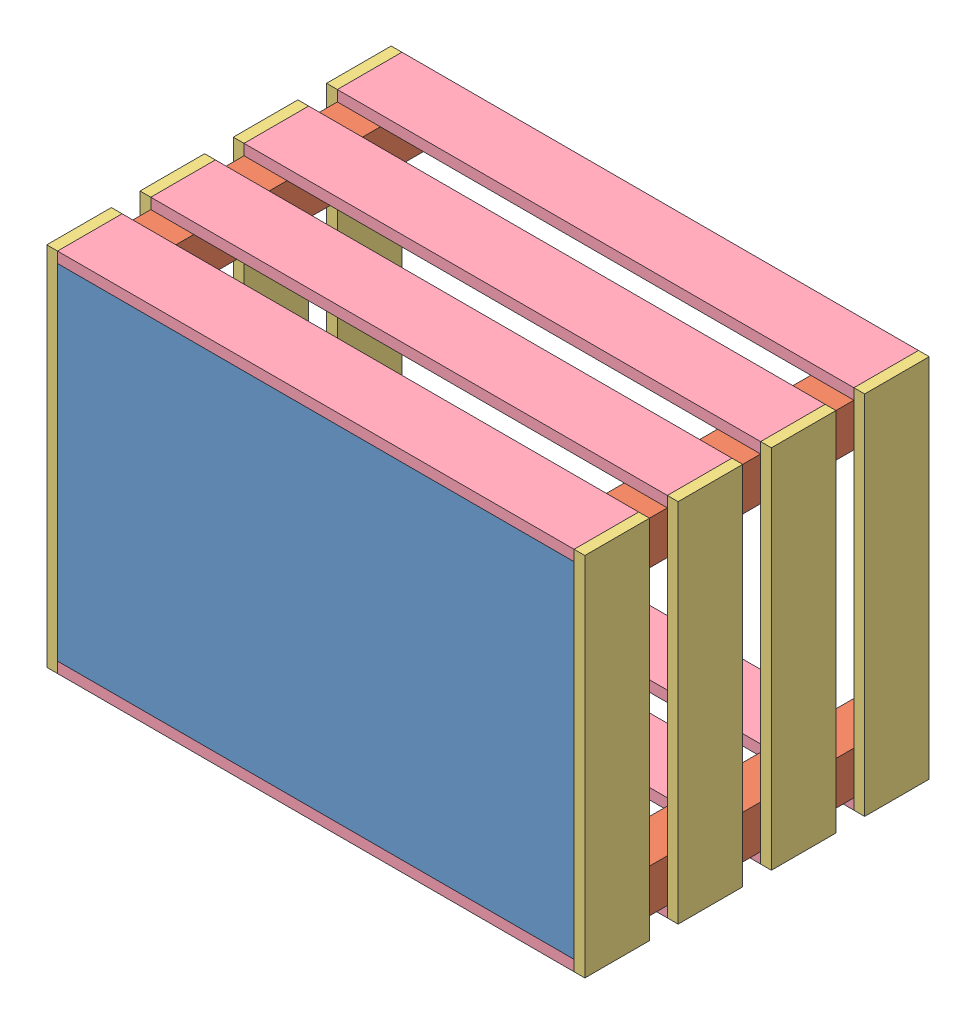
SolidWorks assembly crate, configuration Default. Lengths in mm.
Overall size (317.5 215.9 203.2).
21 component instances, 4 part files, 60 mates.
Components (placement in the parent):
- bottom-1: bottom [Default] at (-1.7472 114.5452 325.1624) size (304.8 203.2 6.35)
- post-1: post [Default] at (-1.7472 114.5452 128.3124) size (25.4 25.4 196.85)
- post-2: post [Default] at (-1.7472 292.3452 128.3124) size (25.4 25.4 196.85)
- post-5: post [Default] at (277.6528 114.5452 128.3124) size (25.4 25.4 196.85)
- post-7: post [Default] at (277.6528 292.3452 128.3124) size (25.4 25.4 196.85)
- side width-1: side width [Default] at (-1.7472 324.0952 293.4124) x (0 -1 0) z (-1 0 0) size (215.9 38.1 6.35)
- side width-2: side width [Default] at (-1.7472 108.1952 166.4124) x (0 1 0) z (-1 0 0) size (215.9 38.1 6.35)
- side width-3: side width [Default] at (-1.7472 324.0952 183.3458) x (0 -1 0) z (-1 0 0) size (215.9 38.1 6.35)
- side width-4: side width [Default] at (-1.7472 324.0952 238.3791) x (0 -1 0) z (-1 0 0) size (215.9 38.1 6.35)
- side width-5: side width [Default] at (309.4028 324.0952 293.4124) x (0 -1 0) z (-1 0 0) size (215.9 38.1 6.35)
- side width-6: side width [Default] at (309.4028 324.0952 238.3791) x (0 -1 0) z (-1 0 0) size (215.9 38.1 6.35)
- side width-7: side width [Default] at (309.4028 324.0952 183.3458) x (0 -1 0) z (-1 0 0) size (215.9 38.1 6.35)
- side width-8: side width [Default] at (309.4028 324.0952 128.3124) x (0 -1 0) z (-1 0 0) size (215.9 38.1 6.35)
- side length-1: side length [Default] at (-1.7472 114.5452 293.4124) x (1 0 0) z (0 -1 0) size (304.8 38.1 6.35)
- side length-2: side length [Default] at (-1.7472 114.5452 183.3458) x (1 0 0) z (0 -1 0) size (304.8 38.1 6.35)
- side length-3: side length [Default] at (-1.7472 114.5452 238.3791) x (1 0 0) z (0 -1 0) size (304.8 38.1 6.35)
- side length-4: side length [Default] at (-1.7472 114.5452 128.3124) x (1 0 0) z (0 -1 0) size (304.8 38.1 6.35)
- side length-5: side length [Default] at (-1.7472 324.0952 293.4124) x (1 0 0) z (0 -1 0) size (304.8 38.1 6.35)
- side length-6: side length [Default] at (-1.7472 324.0952 128.3124) x (1 0 0) z (0 -1 0) size (304.8 38.1 6.35)
- side length-7: side length [Default] at (-1.7472 324.0952 183.3458) x (1 0 0) z (0 -1 0) size (304.8 38.1 6.35)
- side length-8: side length [Default] at (-1.7472 324.0952 238.3791) x (1 0 0) z (0 -1 0) size (304.8 38.1 6.35)
Mates (geometry in assembly coordinates):
- Coincident6: coincident anti-aligned: plane of bottom-1 through (-1.7472 114.5452 325.1624) normal (0 0 -1); plane of post-1 through (-1.7472 114.5452 325.1624) normal (0 0 1)
- Coincident7: coincident anti-aligned: plane of bottom-1 through (-1.7472 114.5452 325.1624) normal (0 0 -1); plane of post-2 through (-1.7472 292.3452 325.1624) normal (0 0 1)
- Coincident8: coincident aligned: plane of bottom-1 through (-1.7472 114.5452 331.5124) normal (-1 0 0); plane of post-2 through (-1.7472 292.3452 325.1624) normal (-1 0 0)
- Coincident9: coincident aligned: plane of bottom-1 through (-1.7472 317.7452 331.5124) normal (0 1 0); plane of post-2 through (-1.7472 317.7452 325.1624) normal (0 1 0)
- Coincident10: coincident anti-aligned: plane of bottom-1 through (-1.7472 114.5452 325.1624) normal (0 0 -1); plane of post-5 through (277.6528 114.5452 325.1624) normal (0 0 1)
- Coincident11: coincident aligned: plane of bottom-1 through (303.0528 114.5452 331.5124) normal (1 0 0); plane of post-5 through (303.0528 114.5452 325.1624) normal (1 0 0)
- Coincident12: coincident aligned: plane of bottom-1 through (-1.7472 114.5452 331.5124) normal (0 -1 0); plane of post-5 through (277.6528 114.5452 325.1624) normal (0 -1 0)
- Coincident13: coincident anti-aligned: plane of bottom-1 through (-1.7472 114.5452 325.1624) normal (0 0 -1); plane of post-7 through (277.6528 292.3452 325.1624) normal (0 0 1)
- Coincident14: coincident aligned: plane of bottom-1 through (303.0528 114.5452 331.5124) normal (1 0 0); plane of post-7 through (303.0528 292.3452 325.1624) normal (1 0 0)
- Coincident15: coincident aligned: plane of bottom-1 through (-1.7472 317.7452 331.5124) normal (0 1 0); plane of post-7 through (277.6528 317.7452 325.1624) normal (0 1 0)
- Coincident16: coincident anti-aligned: plane of bottom-1 through (-1.7472 114.5452 331.5124) normal (-1 0 0); plane of side width-1 through (-1.7472 324.0952 293.4124) normal (1 0 0)
- Coincident17: coincident aligned: plane of bottom-1 through (-1.7472 114.5452 331.5124) normal (0 0 1); plane of side width-1 through (-8.0972 324.0952 331.5124) normal (0 0 1)
- Distance1: distance = 6.35 mm aligned: plane of bottom-1 through (-1.7472 317.7452 331.5124) normal (0 1 0); plane of side width-1 through (-8.0972 324.0952 293.4124) normal (0 1 0)
- Coincident21: coincident aligned: plane of side width-1 through (-1.7472 324.0952 293.4124) normal (1 0 0); plane of side width-2 through (-1.7472 108.1952 166.4124) normal (1 0 0)
- Coincident22: coincident aligned: plane of post-2 through (-1.7472 292.3452 128.3124) normal (0 0 -1); plane of side width-2 through (-8.0972 108.1952 128.3124) normal (0 0 -1)
- Coincident23: coincident aligned: plane of side width-1 through (-8.0972 324.0952 293.4124) normal (0 1 0); plane of side width-2 through (-8.0972 324.0952 166.4124) normal (0 1 0)
- Coincident30: coincident aligned: plane of side width-1 through (-1.7472 324.0952 293.4124) normal (1 0 0); plane of side width-4 through (-1.7472 324.0952 238.3791) normal (1 0 0)
- Coincident31: coincident aligned: plane of side width-1 through (-1.7472 324.0952 293.4124) normal (1 0 0); plane of side width-3 through (-1.7472 324.0952 183.3458) normal (1 0 0)
- Coincident32: coincident aligned: plane of side width-1 through (-8.0972 324.0952 293.4124) normal (0 1 0); plane of side width-4 through (-8.0972 324.0952 238.3791) normal (0 1 0)
- Coincident33: coincident aligned: plane of side width-1 through (-8.0972 324.0952 293.4124) normal (0 1 0); plane of side width-3 through (-8.0972 324.0952 183.3458) normal (0 1 0)
- Distance4: distance = 16.9333 mm anti-aligned: plane of side width-4 through (-8.0972 324.0952 276.4791) normal (0 0 1); plane of side width-1 through (-8.0972 324.0952 293.4124) normal (0 0 -1)
- Distance5: distance = 16.9333 mm anti-aligned: plane of side width-4 through (-8.0972 324.0952 238.3791) normal (0 0 -1); plane of side width-3 through (-8.0972 324.0952 221.4458) normal (0 0 1)
- Coincident37: coincident anti-aligned: plane of bottom-1 through (303.0528 114.5452 331.5124) normal (1 0 0); plane of side width-5 through (303.0528 324.0952 293.4124) normal (-1 0 0)
- Coincident38: coincident aligned: plane of bottom-1 through (-1.7472 114.5452 331.5124) normal (0 0 1); plane of side width-5 through (303.0528 324.0952 331.5124) normal (0 0 1)
- Distance7: distance = 6.35 mm aligned: plane of post-7 through (277.6528 317.7452 325.1624) normal (0 1 0); plane of side width-5 through (303.0528 324.0952 293.4124) normal (0 1 0)
- Coincident41: coincident aligned: plane of side width-5 through (303.0528 324.0952 293.4124) normal (-1 0 0); plane of side width-6 through (303.0528 324.0952 238.3791) normal (-1 0 0)
- Coincident42: coincident aligned: plane of side width-5 through (303.0528 324.0952 293.4124) normal (-1 0 0); plane of side width-7 through (303.0528 324.0952 183.3458) normal (-1 0 0)
- Coincident43: coincident aligned: plane of side width-5 through (303.0528 324.0952 293.4124) normal (-1 0 0); plane of side width-8 through (303.0528 324.0952 128.3124) normal (-1 0 0)
- Coincident44: coincident aligned: plane of side width-5 through (303.0528 324.0952 293.4124) normal (0 1 0); plane of side width-6 through (303.0528 324.0952 238.3791) normal (0 1 0)
- Coincident45: coincident aligned: plane of side width-5 through (303.0528 324.0952 293.4124) normal (0 1 0); plane of side width-7 through (303.0528 324.0952 183.3458) normal (0 1 0)
- Coincident46: coincident aligned: plane of side width-5 through (303.0528 324.0952 293.4124) normal (0 1 0); plane of side width-8 through (303.0528 324.0952 128.3124) normal (0 1 0)
- Coincident47: coincident aligned: plane of post-7 through (277.6528 292.3452 128.3124) normal (0 0 -1); plane of side width-8 through (303.0528 324.0952 128.3124) normal (0 0 -1)
- Distance8: distance = 16.9333 mm anti-aligned: plane of side width-5 through (303.0528 324.0952 293.4124) normal (0 0 -1); plane of side width-6 through (303.0528 324.0952 276.4791) normal (0 0 1)
- Distance9: distance = 16.9333 mm anti-aligned: plane of side width-7 through (303.0528 324.0952 221.4458) normal (0 0 1); plane of side width-6 through (303.0528 324.0952 238.3791) normal (0 0 -1)
- Coincident51: coincident anti-aligned: plane of post-5 through (277.6528 114.5452 325.1624) normal (0 -1 0); plane of side length-1 through (-1.7472 114.5452 293.4124) normal (0 1 0)
- Coincident52: coincident aligned: plane of bottom-1 through (-1.7472 114.5452 331.5124) normal (0 0 1); plane of side length-1 through (-1.7472 108.1952 331.5124) normal (0 0 1)
- Coincident55: coincident aligned: plane of bottom-1 through (-1.7472 114.5452 331.5124) normal (0 -1 0); plane of post-1 through (-1.7472 114.5452 325.1624) normal (0 -1 0)
- Coincident56: coincident anti-aligned: plane of post-1 through (-1.7472 114.5452 325.1624) normal (-1 0 0); plane of side width-1 through (-1.7472 324.0952 293.4124) normal (1 0 0)
- Coincident57: coincident aligned: plane of post-1 through (-1.7472 114.5452 325.1624) normal (-1 0 0); plane of side length-1 through (-1.7472 108.1952 293.4124) normal (-1 0 0)
- Coincident58: coincident aligned: plane of side length-1 through (-1.7472 114.5452 293.4124) normal (0 1 0); plane of side length-4 through (-1.7472 114.5452 128.3124) normal (0 1 0)
- Coincident59: coincident aligned: plane of side length-1 through (-1.7472 114.5452 293.4124) normal (0 1 0); plane of side length-2 through (-1.7472 114.5452 183.3458) normal (0 1 0)
- Coincident60: coincident aligned: plane of side length-1 through (-1.7472 114.5452 293.4124) normal (0 1 0); plane of side length-3 through (-1.7472 114.5452 238.3791) normal (0 1 0)
- Coincident61: coincident aligned: plane of post-1 through (-1.7472 114.5452 325.1624) normal (-1 0 0); plane of side length-4 through (-1.7472 108.1952 128.3124) normal (-1 0 0)
- Coincident62: coincident aligned: plane of post-1 through (-1.7472 114.5452 325.1624) normal (-1 0 0); plane of side length-2 through (-1.7472 108.1952 183.3458) normal (-1 0 0)
- Coincident63: coincident aligned: plane of post-1 through (-1.7472 114.5452 325.1624) normal (-1 0 0); plane of side length-3 through (-1.7472 108.1952 238.3791) normal (-1 0 0)
- Coincident64: coincident aligned: plane of post-1 through (-1.7472 114.5452 128.3124) normal (0 0 -1); plane of side length-4 through (-1.7472 108.1952 128.3124) normal (0 0 -1)
- Distance12: distance = 16.9333 mm anti-aligned: plane of side length-1 through (-1.7472 108.1952 293.4124) normal (0 0 -1); plane of side length-3 through (-1.7472 108.1952 276.4791) normal (0 0 1)
- Distance13: distance = 16.9333 mm anti-aligned: plane of side length-3 through (-1.7472 108.1952 238.3791) normal (0 0 -1); plane of side length-2 through (-1.7472 108.1952 221.4458) normal (0 0 1)
- Coincident71: coincident anti-aligned: plane of bottom-1 through (-1.7472 317.7452 331.5124) normal (0 1 0); plane of side length-5 through (-1.7472 317.7452 293.4124) normal (0 -1 0)
- Coincident72: coincident aligned: plane of bottom-1 through (-1.7472 114.5452 331.5124) normal (0 0 1); plane of side length-5 through (-1.7472 317.7452 331.5124) normal (0 0 1)
- Coincident73: coincident aligned: plane of post-7 through (303.0528 292.3452 325.1624) normal (1 0 0); plane of side length-5 through (303.0528 317.7452 293.4124) normal (1 0 0)
- Coincident74: coincident aligned: plane of side length-5 through (-1.7472 317.7452 293.4124) normal (0 -1 0); plane of side length-7 through (-1.7472 317.7452 399.3489) normal (0 -1 0)
- Coincident75: coincident aligned: plane of side length-5 through (-1.7472 317.7452 293.4124) normal (0 -1 0); plane of side length-6 through (-1.7472 317.7452 128.3124) normal (0 -1 0)
- Coincident76: coincident aligned: plane of side length-5 through (-1.7472 317.7452 293.4124) normal (0 -1 0); plane of side length-8 through (-1.7472 317.7452 238.3791) normal (0 -1 0)
- Coincident77: coincident aligned: plane of post-7 through (303.0528 292.3452 325.1624) normal (1 0 0); plane of side length-7 through (303.0528 317.7452 399.3489) normal (1 0 0)
- Coincident79: coincident aligned: plane of post-7 through (303.0528 292.3452 325.1624) normal (1 0 0); plane of side length-6 through (303.0528 317.7452 128.3124) normal (1 0 0)
- Coincident80: coincident aligned: plane of post-7 through (303.0528 292.3452 325.1624) normal (1 0 0); plane of side length-8 through (303.0528 317.7452 238.3791) normal (1 0 0)
- Coincident82: coincident aligned: plane of post-7 through (277.6528 292.3452 128.3124) normal (0 0 -1); plane of side length-6 through (-1.7472 317.7452 128.3124) normal (0 0 -1)
- Distance14: distance = 16.9333 mm anti-aligned: plane of side length-5 through (-1.7472 317.7452 293.4124) normal (0 0 -1); plane of side length-8 through (-1.7472 317.7452 276.4791) normal (0 0 1)
- Distance15: distance = 16.9333 mm anti-aligned: plane of side length-8 through (-1.7472 317.7452 238.3791) normal (0 0 -1); plane of side length-7 through (-1.7472 317.7452 221.4458) normal (0 0 1)
